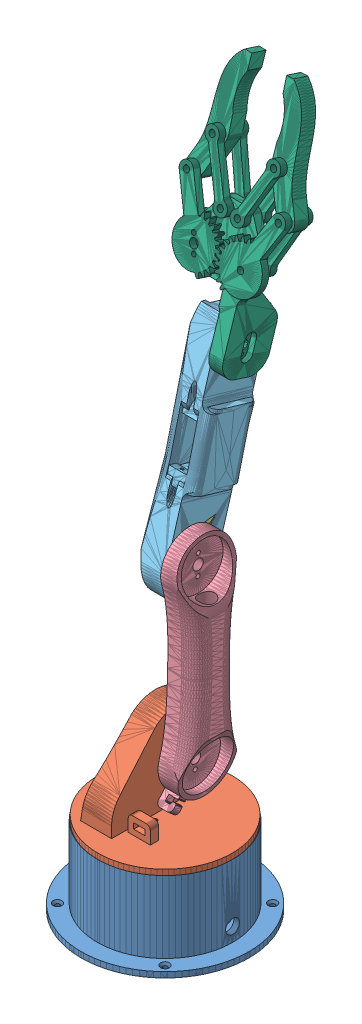
SolidWorks assembly Assem1, configuration Default. Lengths in mm.
Overall size (121.24 482.88 155.51).
8 component instances, 6 part files, 18 mates.
Components (placement in the parent):
- base0-1: base0 [Default] at (48.9065 45.2888 96.9938) size (121.24 56 121.25)
- waist0-1: waist0 [Default] at (46.3326 89.214 97.2003) x (0.999993 0 0.003863) z (-0.003863 0 0.999993) size (96.99 64.78 97)
- cube-1: cube [Default] at (26.8725 96.3222 97.6088) x (0.002731 0.707107 -0.707102) z (0.999993 0 0.003863) size (41 21 12)
- Arm 01-1: Arm 01 [Default] at (48.4912 115.8634 77.7047) x (0.003862 -0.015869 -0.999867) z (0.999993 0 0.003863) size (43.22 166.68 21)
- Arm 02-1: Arm 02 [Default] at (42.4751 235.7246 73.4562) x (-0.999904 0.005507 0.012694) z (-0.013732 -0.281887 -0.959349) size (27.46 167.91 39.33)
- cube-3: cube [Default] at (30.5292 222.6648 66.2782) x (0.001704 0.959432 -0.281936) z (0.999992 -0.000585 0.004053) size (41 21 12)
- cube-4: cube [Default] at (40.7823 367.3354 24.8469) x (-0.001704 -0.959432 0.281936) z (-0.999992 0.000585 -0.004053) size (41 21 12)
- Gripper.0011-2: Gripper.0011 [Default] at (48.0986 357.2184 43.0343) x (0.999991 -0.000488 0.004128) z (-0.000488 -1 -0.000003) size (79.32 59.77 173.34)
Mates (geometry in assembly coordinates):
- Parallel1: parallel aligned: plane of base0-1 through (48.9065 85.214 96.9938) normal (0 1 0); plane of waist0-1 through (46.3326 89.214 97.2003) normal (0 1 0)
- Coincident2: coincident: plane of base0-1 through (48.9065 85.214 96.9938) normal (0 1 0); line of waist0-1 through (94.8729 85.214 95.2529) axis (-0.072325 0 -0.997381)
- Coincident3: coincident: line of base0-1 through (94.7743 85.214 100.8738) axis (0.049595 0 -0.998769); plane of waist0-1 through (94.7599 85.214 101.1653) normal (0.998769 0 0.049595)
- Parallel4: parallel aligned: plane of base0-1 through (48.9065 85.214 96.9938) normal (0 1 0); plane of waist0-1 through (46.3326 89.214 97.2003) normal (0 1 0)
- Coincident8: coincident anti-aligned: plane of waist0-1 through (40.4139 96.3222 97.6611) normal (0.002731 0.707107 -0.707102); plane of cube-1 through (38.8724 96.3222 97.6551) normal (-0.002731 -0.707107 0.707102)
- Coincident9: coincident: plane of waist0-1 through (40.3566 111.1714 112.5102) normal (0.002731 -0.707107 -0.707101); line of cube-1 through (26.9271 140.1628 83.4667) axis (-0.002731 -0.707107 0.707102)
- Parallel5: parallel: plane of waist0-1 through (42.4158 89.214 97.1852) normal (0.999993 0 0.003863); line of Arm 01-1 through (42.4949 119.4688 76.6917) axis (-0.003842 0.10295 0.994679)
- Coincident12: coincident: plane of waist0-1 through (-1.99 125.4903 74.1782) normal (-0.003853 -0.071333 0.997445); line of Arm 01-1 through (42.5065 116.3791 73.6985) axis (0.000276 -0.997453 -0.071333)
- Coincident13: coincident: line of waist0-1 through (42.4759 149.9294 81.6229) axis (-0.003861 0.027752 0.999607); plane of Arm 01-1 through (42.4911 115.8634 77.6815) normal (-0.999993 0 -0.003863)
- Coincident20: coincident aligned: plane of Arm 01-1 through (48.4508 118.8836 87.9831) normal (0.003764 -0.281919 -0.959431); plane of Arm 02-1 through (42.5467 230.3612 55.2034) normal (0.003764 -0.281919 -0.959431)
- Coincident21: coincident: plane of Arm 01-1 through (42.4911 115.8634 77.6815) normal (-0.999993 0 -0.003863); line of Arm 02-1 through (42.4739 237.9897 82.1456) axis (-0.000849 -0.975549 0.219781)
- Coincident25: coincident anti-aligned: line of Arm 02-1 through (29.4511 228.5861 86.422) axis (0.999992 -0.000585 0.004053); line of cube-3 through (42.4509 228.5785 86.4747) axis (-0.999992 0.000585 -0.004053)
- Coincident28: coincident: point of Arm 01-1; plane of cube-3 through (42.5291 222.6578 66.3268) normal (0.999992 -0.000585 0.004053)
- Coincident29: coincident anti-aligned: plane of Arm 02-1 through (42.6438 330.6828 45.552) normal (0.001704 0.959432 -0.281936); plane of cube-4 through (28.7125 328.0057 36.3576) normal (-0.001704 -0.959432 0.281936)
- Coincident30: coincident anti-aligned: plane of Arm 02-1 through (42.4324 238.9601 84.4663) normal (0.003724 -0.281941 -0.959425); plane of cube-4 through (28.7042 373.2632 44.9462) normal (-0.003724 0.281941 0.959425)
- Coincident31: coincident: unknown of Arm 02-1; plane of cube-4 through (40.7823 367.3354 24.8469) normal (0.999992 -0.000585 0.004053)
- Parallel18: parallel: plane of cube-4 through (40.7823 367.3354 24.8469) normal (0.999992 -0.000585 0.004053); line of Gripper.0011-2 through (72.062 354.5791 42.0182) axis (0.003582 0.604819 -0.796355)
- Coincident37: coincident: line of Arm 02-1 through (42.7951 368.7503 21.8452) axis (0.003812 -0.288249 -0.957548); plane of Gripper.0011-2 through (42.7021 357.2211 43.012) normal (-0.999991 0.000487 -0.004128)
